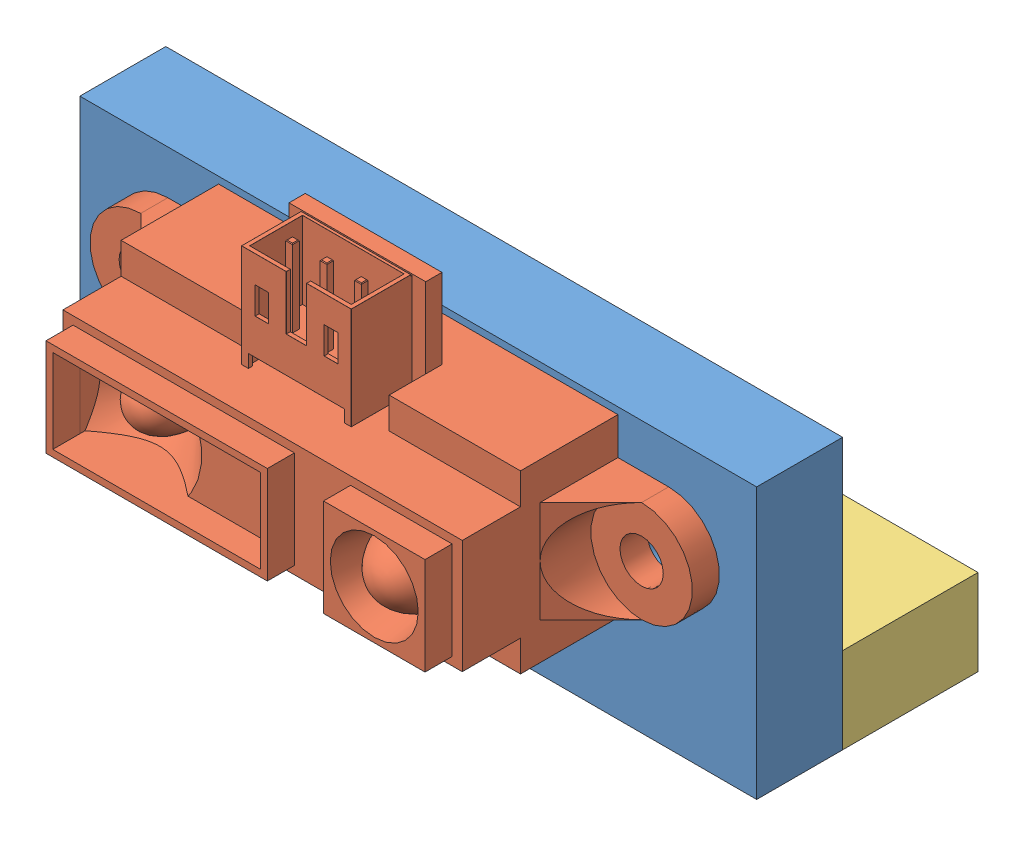
SolidWorks assembly EnsambleSharp, configuration Predeterminado. Lengths in mm.
Overall size (50 25.4 29.85).
3 component instances, 3 part files, 6 mates.
Components (placement in the parent):
- BaseSharp1-1: BaseSharp1 [Predeterminado] at (-5.7069 1.07 46.825) size (50 20 6.35)
- Sharp-2: Sharp [Default] at (-5.7069 4.07 53.175) x (-1 0 0) z (0 0 1) size (44.5 18.9 13.5)
- basesharp2-1: basesharp2 [Predeterminado] at (-5.7069 -2.58 41.825) x (1 0 0) z (0 -1 0) size (50 10 6.35)
Mates (geometry in assembly coordinates):
- Concéntrica2: concentric: cylinder of BaseSharp1-1 through (-24.2069 4.07 46.825) axis (0 0 1) radius 1.6; cylinder of Sharp-2 through (-24.2069 4.07 66.675) axis (0 0 -1) radius 1.6
- Concéntrica3: concentric: cylinder of BaseSharp1-1 through (12.7931 4.07 46.825) axis (0 0 1) radius 1.6; cylinder of Sharp-2 through (12.7931 4.07 66.675) axis (0 0 -1) radius 1.6
- Coincidente1: coincident: plane of BaseSharp1-1 through (-5.7069 1.07 46.825) normal (0 0 -1); plane of basesharp2-1 through (-30.7069 -8.93 46.825) normal (0 0 1)
- Coincidente2: coincident: plane of BaseSharp1-1 through (19.2931 -8.93 53.175) normal (1 0 0); plane of basesharp2-1 through (19.2931 -8.93 36.825) normal (1 0 0)
- Coincidente3: coincident: plane of BaseSharp1-1 through (-30.7069 -8.93 53.175) normal (0 -1 0); plane of basesharp2-1 through (-5.7069 -8.93 41.825) normal (0 -1 0)
- Coincidente4: coincident: plane of BaseSharp1-1 through (-5.7069 1.07 53.175) normal (0 0 1); plane of Sharp-2 through (12.7931 4.07 53.175) normal (0 0 -1)
